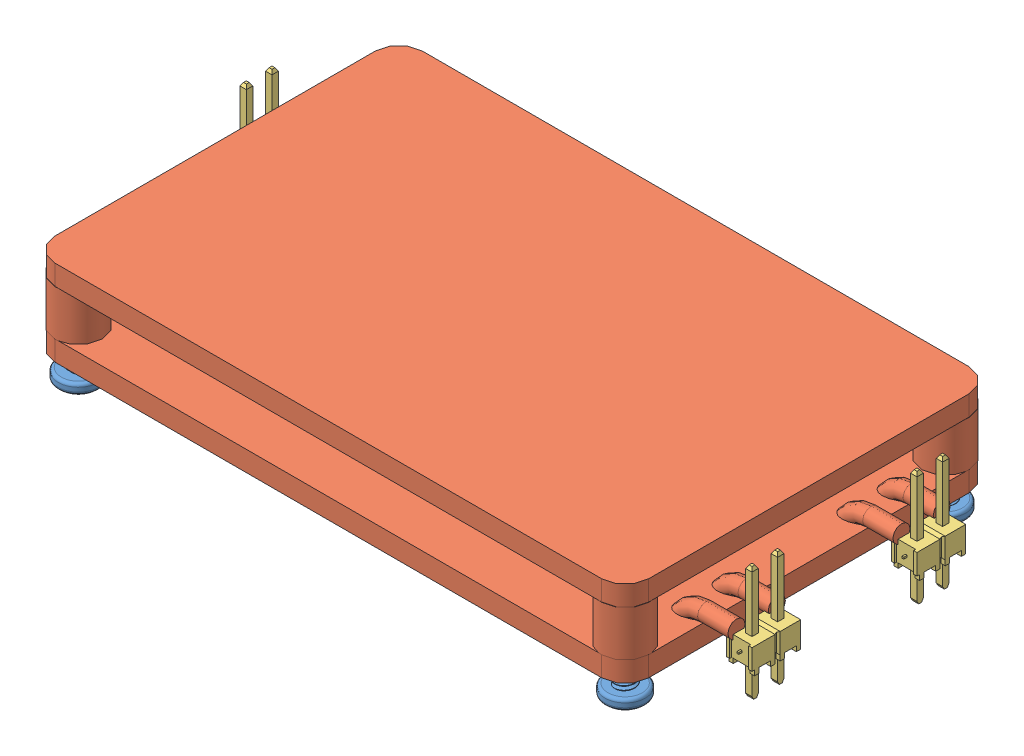
SolidWorks assembly BatteryMonitorAssembly, configuration Default. Lengths in mm.
Overall size (68.99 11.71 36.95).
8 component instances, 3 part files, 15 mates.
Components (placement in the parent):
- 92000A012_Passivated 18-8 Stainless Steel Pan Head Phillips Screws-1: 92000A012_Passivated 18-8 Stainless Steel Pan Head Phillips Screws [92000A012] at (-27.09 3.4 15.875) x (0.702544 0 0.711641) z (0 -1 0) size (4 4 6.68)
- BatteryMonitor-1: BatteryMonitor [Default] at origin size (64.83 8.5 36.45)
- 92000A012_Passivated 18-8 Stainless Steel Pan Head Phillips Screws-2: 92000A012_Passivated 18-8 Stainless Steel Pan Head Phillips Screws [92000A012] at (27.09 3.4 15.875) x (-0.99989 0 -0.014831) z (0 -1 0) size (4 4 6.68)
- 92000A012_Passivated 18-8 Stainless Steel Pan Head Phillips Screws-3: 92000A012_Passivated 18-8 Stainless Steel Pan Head Phillips Screws [92000A012] at (27.09 3.4 -15.875) x (-0.209713 0 0.977763) z (0 -1 0) size (4 4 6.68)
- 92000A012_Passivated 18-8 Stainless Steel Pan Head Phillips Screws-4: 92000A012_Passivated 18-8 Stainless Steel Pan Head Phillips Screws [92000A012] at (-27.09 3.4 -15.875) x (0.991519 0 -0.12996) z (0 -1 0) size (4 4 6.68)
- TSW-150-23-T-S_2-1: TSW-150-23-T-S_2 [Default] at (-33.225 0 -69.135) x (0 0 -1) z (1 0 0) size (5.21 11.3 2.54)
- TSW-150-23-T-S_2-3: TSW-150-23-T-S_2 [Default] at (33.225 0 -52.785) x (0 0 -1) z (1 0 0) size (5.21 11.3 2.54)
- TSW-150-23-T-S_2-4: TSW-150-23-T-S_2 [Default] at (33.225 0 -69.135) x (0 0 -1) z (1 0 0) size (5.21 11.3 2.54)
Mates (geometry in assembly coordinates):
- Coincident1: coordinate: unknown of BatteryMonitor-1
- Concentric1: concentric aligned: circle of BatteryMonitor-1; cylinder of 92000A012_Passivated 18-8 Stainless Steel Pan Head Phillips Screws-4 through (-27.09 3.4 -15.875) axis (0 1 0) radius 2
- Concentric2: concentric anti-aligned: cylinder of 92000A012_Passivated 18-8 Stainless Steel Pan Head Phillips Screws-1 through (-27.09 3.4 15.875) axis (0 1 0) radius 2; cylinder of BatteryMonitor-1 through (-27.09 2 15.875) axis (0 -1 0) radius 2.325
- Concentric3: concentric aligned: circle of BatteryMonitor-1; circle of 92000A012_Passivated 18-8 Stainless Steel Pan Head Phillips Screws-3
- Concentric4: concentric anti-aligned: cylinder of BatteryMonitor-1 through (27.09 2 15.875) axis (0 -1 0) radius 2.325; circle of 92000A012_Passivated 18-8 Stainless Steel Pan Head Phillips Screws-2
- Coincident2: coincident aligned: plane of 92000A012_Passivated 18-8 Stainless Steel Pan Head Phillips Screws-2 through (27.09 -1.6 15.875) normal (0 1 0); plane of 92000A012_Passivated 18-8 Stainless Steel Pan Head Phillips Screws-3 through (27.09 -1.6 -15.875) normal (0 1 0)
- Coincident3: coincident aligned: plane of 92000A012_Passivated 18-8 Stainless Steel Pan Head Phillips Screws-1 through (-27.09 -1.6 15.875) normal (0 1 0); plane of 92000A012_Passivated 18-8 Stainless Steel Pan Head Phillips Screws-2 through (27.09 -1.6 15.875) normal (0 1 0)
- Coincident4: coincident aligned: plane of 92000A012_Passivated 18-8 Stainless Steel Pan Head Phillips Screws-1 through (-27.09 -1.6 15.875) normal (0 1 0); plane of 92000A012_Passivated 18-8 Stainless Steel Pan Head Phillips Screws-4 through (-27.09 -1.6 -15.875) normal (0 1 0)
- Distance1: distance = 1.6 mm anti-aligned: plane of 92000A012_Passivated 18-8 Stainless Steel Pan Head Phillips Screws-1 through (-27.09 -1.6 15.875) normal (0 1 0); plane of BatteryMonitor-1 through (26.565 0 10.175) normal (0 -1 0)
- Coincident5: coincident aligned: plane of BatteryMonitor-1 through (26.565 0 10.175) normal (0 -1 0); plane of TSW-150-23-T-S_2-1 through (-33.225 0 -69.135) normal (0 -1 0)
- Coincident9: coincident aligned: plane of TSW-150-23-T-S_2-3 through (35.765 0.508 10.4641) normal (0 -1 0); plane of TSW-150-23-T-S_2-4 through (35.765 0.508 -10.0323) normal (0 -1 0)
- Coincident10: coincident aligned: plane of TSW-150-23-T-S_2-3 through (31.955 2.54 -116.285) normal (-1 0 0); plane of TSW-150-23-T-S_2-4 through (31.955 2.54 -132.635) normal (-1 0 0)
- Distance2: distance = 2.54 mm anti-aligned: plane of BatteryMonitor-1 through (29.415 2 0) normal (1 0 0); plane of TSW-150-23-T-S_2-3 through (31.955 2.54 -116.285) normal (-1 0 0)
- Coincident16: coincident: line of TSW-150-23-T-S_2-4 through (34.241 2.286 -8.175) axis (-1 0 0)
- Width4: width aligned: plane of BatteryMonitor-1 through (-27.09 8.5 -18.2) normal (0 0 -1); plane of BatteryMonitor-1 through (-27.09 8.5 18.2) normal (0 0 1); plane of TSW-150-23-T-S_2-4 through (35.765 8.382 -9.7625) normal (0 0 -1); plane of TSW-150-23-T-S_2-3 through (33.5425 8.382 9.7625) normal (0 0 1)
